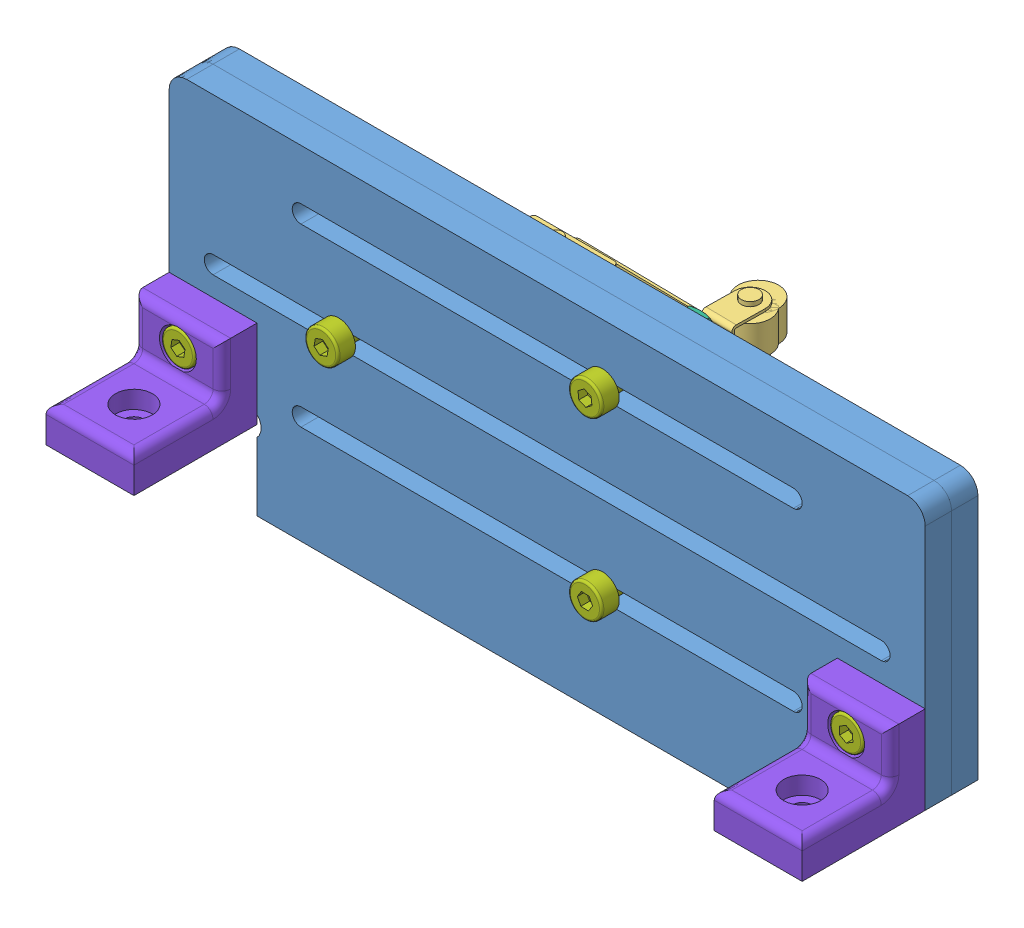
SolidWorks assembly fdc_ouvert, configuration Défaut. Lengths in mm.
Overall size (86 39 42.4).
21 component instances, 8 part files, 44 mates.
Components (placement in the parent):
- fdc-platine-1: fdc-platine [Défaut] at (140.8628 -70 0) x (0 0 1) z (0 -1 0) size (3 86 39)
- Grove microswitch v1.0-1: Grove microswitch v1.0 [Défaut] at (-48.6908 22.25 -3.344) x (-1 0 0) z (0 -1 0) size (41.8 22.4 23.6)
  - PCB grove 20x40-1: PCB grove 20x40 [Défaut] at (-1.988 -1.344 0) size (41.8 1.6 23.6)
  - microswitch 10T85-1: microswitch 10T85 [Défaut] at (9.562 0.256 0) size (22.48 22.4 6.4)
  - Connecteur Grove (coudé CMS)-1: Connecteur Grove (coudé CMS) [Défaut] at (-21.488 0.256 0) x (0 0 -1) z (0 1 0) size (12 10 5)
- entretoise-grove-1: entretoise-grove [Défaut] at (-66.7028 22.25 -2) x (1 0.000242 0) z (0 0 1) size (4 4 2)
- entretoise-grove-2: entretoise-grove [Défaut] at (-36.7028 32.25 -2) size (4 4 2)
- entretoise-grove-3: entretoise-grove [Défaut] at (-36.7028 12.25 -2) size (4 4 2)
- ecrou-h-2: ecrou-h [6007 HU M2] at (-36.7028 32.25 -5.2) x (-0.866025 0.5 0) z (-0.5 -0.866025 0) size (4 1.6 4.62)
- ecrou-h-3: ecrou-h [6007 HU M2] at (-36.7028 12.25 -5.2) x (0.866025 0.5 0) z (-0.5 0.866025 0) size (4 1.6 4.62)
- vis-chc-1: vis-chc [Vis CHC M2x12] at (-36.7028 32.25 6) x (0.144676 -0.989479 0) z (-0.989479 -0.144676 0) size (3.8 14 3.8)
- vis-chc-2: vis-chc [Vis CHC M2x12] at (-36.7028 12.25 6) x (0.999846 -0.017534 0) z (-0.017534 -0.999846 0) size (3.8 14 3.8)
- vis-chc-3: vis-chc [Vis CHC M2x12] at (-66.7028 22.25 6) x (-0.77641 0.630228 0) z (0.630228 0.77641 0) size (3.8 14 3.8)
- vis-chc-5: vis-chc [Vis CHC M2x10] at (-5 16 8) x (0.048861 -0.998806 0) z (-0.998806 -0.048861 0) size (3.8 12 3.8)
- vis-chc-6: vis-chc [Vis CHC M2x10] at (-81 16 8) x (-0.923728 -0.383049 0) z (-0.383049 0.923728 0) size (3.8 12 3.8)
- ecrou-h-6: ecrou-h [6007 HU M2] at (-81 16 -1.6) x (1 0 0) z (0 1 0) size (4 1.6 4.62)
- ecrou-h-8: ecrou-h [6007 HU M2] at (-5 16 -1.6) x (1 0 0) z (0 1 0) size (4 1.6 4.62)
- fdc-platine-2: fdc-platine [Défaut] at (140.8628 -70 3) x (0 0 1) z (0 -1 0) size (3 86 39)
- ecrou-h-4: ecrou-h [6007 HU M2] at (-66.7028 22.25 -5.2) x (1 0 0) z (0 1 0) size (4 1.6 4.62)
- equerre-basse-1: equerre-basse [Défaut] at (-81 9 6) size (10 10 14)
- equerre-basse-2: equerre-basse [Défaut] at (-5 9 6) size (10 10 14)
Mates (geometry in assembly coordinates):
- Coaxiale1: concentric anti-aligned: cylinder of Grove microswitch v1.0-1/PCB grove 20x40-1 through (-36.7028 12.25 -3.6) axis (0 0 1) radius 1.1; cylinder of entretoise-grove-3 through (-36.7028 12.25 0) axis (0 0 -1) radius 1.2
- Coïncidente4: coincident anti-aligned: plane of Grove microswitch v1.0-1/PCB grove 20x40-1 through (-46.7028 22.25 -2) normal (0 0 1); plane of entretoise-grove-3 through (-36.7028 12.25 -2) normal (0 0 -1)
- Coaxiale2: concentric anti-aligned: cylinder of Grove microswitch v1.0-1/PCB grove 20x40-1 through (-66.7028 22.25 -3.6) axis (0 0 1) radius 1.1; cylinder of entretoise-grove-1 through (-66.7028 22.25 0) axis (0 0 -1) radius 1.2
- Coïncidente5: coincident anti-aligned: plane of Grove microswitch v1.0-1/PCB grove 20x40-1 through (-46.7028 22.25 -2) normal (0 0 1); plane of entretoise-grove-1 through (-66.7028 22.25 -2) normal (0 0 -1)
- Coaxiale3: concentric anti-aligned: cylinder of Grove microswitch v1.0-1/PCB grove 20x40-1 through (-36.7028 32.25 -3.6) axis (0 0 1) radius 1.1; cylinder of entretoise-grove-2 through (-36.7028 32.25 0) axis (0 0 -1) radius 1.2
- Coïncidente6: coincident anti-aligned: plane of Grove microswitch v1.0-1/PCB grove 20x40-1 through (-46.7028 22.25 -2) normal (0 0 1); plane of entretoise-grove-2 through (-36.7028 32.25 -2) normal (0 0 -1)
- Coïncidente7: coincident anti-aligned: plane of cfc-platine-1 through (-8.8686 8.8686 0) normal (0 0 -1); plane of entretoise-grove-1 through (-66.7028 22.25 0) normal (0 0 1)
- Parallèle4: parallel aligned: plane of cfc-platine-1 through (-86 39 3) normal (-1 0 0); plane of Grove microswitch v1.0-1/PCB grove 20x40-1 through (-66.7028 22.25 -3.6) normal (-1 0 0)
- Parallèle3: parallel aligned: plane of cfc-platine-1 through (-10 0 3) normal (0 -1 0); plane of Grove microswitch v1.0-1/PCB grove 20x40-1 through (-46.7028 12.25 -3.6) normal (0 -1 0)
- Coaxiale4: concentric aligned: cylinder of Grove microswitch v1.0-1/PCB grove 20x40-1 through (-36.7028 32.25 -3.6) axis (0 0 1) radius 1.1; cylinder of vis-chc-1 through (-36.7028 32.25 -6) axis (0 0 1) radius 1
- Coaxiale5: concentric aligned: cylinder of Grove microswitch v1.0-1/PCB grove 20x40-1 through (-66.7028 22.25 -3.6) axis (0 0 1) radius 1.1; cylinder of vis-chc-3 through (-66.7028 22.25 -6) axis (0 0 1) radius 1
- Coaxiale6: concentric aligned: cylinder of Grove microswitch v1.0-1/PCB grove 20x40-1 through (-36.7028 12.25 -3.6) axis (0 0 1) radius 1.1; cylinder of vis-chc-2 through (-36.7028 12.25 -6) axis (0 0 1) radius 1
- Coaxiale7: concentric anti-aligned: cylinder of ecrou-h-2 through (-36.7028 32.25 -3.6) axis (0 0 -1) radius 0.7835; cylinder of vis-chc-1 through (-36.7028 32.25 -6) axis (0 0 1) radius 1
- Coaxiale8: concentric anti-aligned: cylinder of ecrou-h-3 through (-36.7028 12.25 -3.6) axis (0 0 -1) radius 0.7835; cylinder of vis-chc-2 through (-36.7028 12.25 -6) axis (0 0 1) radius 1
- Parallèle5: parallel aligned: plane of cfc-platine-1 through (0 39 3) normal (0 1 0); plane of ecrou-h-2 through (-37.8575 34.25 -3.6) normal (0 1 0)
- Parallèle7: parallel aligned: plane of ecrou-h-2 through (-37.8575 34.25 -3.6) normal (0 1 0); plane of ecrou-h-3 through (-37.8575 14.25 -3.6) normal (0 1 0)
- Tangent1: tangent anti-aligned: plane of cfc-platine-1 through (-15 31.25 3) normal (0 1 0); cylinder of vis-chc-1 through (-36.7028 32.25 -6) axis (0 0 1) radius 1
- Coïncidente17: coincident anti-aligned: plane of cfc-platine-1 through (-8.8686 8.8686 3) normal (0 0 1); plane of cfc-platine-2 through (-8.8686 8.8686 3) normal (0 0 -1)
- Coïncidente19: coincident aligned: plane of cfc-platine-1 through (-86 39 3) normal (-1 0 0); plane of cfc-platine-2 through (-86 39 6) normal (-1 0 0)
- Coïncidente20: coincident aligned: plane of cfc-platine-1 through (0 39 3) normal (0 1 0); plane of cfc-platine-2 through (0 39 6) normal (0 1 0)
- Coïncidente21: coincident anti-aligned: plane of vis-chc-3 through (-66.7028 22.25 6) normal (0 0 -1); plane of cfc-platine-2 through (-8.8686 8.8686 6) normal (0 0 1)
- Coaxiale9: concentric anti-aligned: cylinder of vis-chc-3 through (-66.7028 22.25 -6) axis (0 0 1) radius 1; cylinder of ecrou-h-4 through (-66.7028 22.25 -3.6) axis (0 0 -1) radius 0.7835
- Parallèle8: parallel aligned: plane of Grove microswitch v1.0-1/microswitch 10T85-1 through (-64.7028 19.25 -13.9) normal (-1 0 0); plane of ecrou-h-4 through (-68.7028 21.0953 -3.6) normal (-1 0 0)
- Coïncidente23: coincident anti-aligned: plane of Grove microswitch v1.0-1/PCB grove 20x40-1 through (-46.7028 22.25 -3.6) normal (0 0 -1); plane of ecrou-h-4 through (-64.7028 21.0953 -3.6) normal (0 0 1)
- Coïncidente24: coincident anti-aligned: plane of vis-chc-1 through (-36.7028 32.25 6) normal (0 0 -1); plane of cfc-platine-2 through (-8.8686 8.8686 6) normal (0 0 1)
- Coïncidente25: coincident anti-aligned: plane of Grove microswitch v1.0-1/PCB grove 20x40-1 through (-46.7028 22.25 -3.6) normal (0 0 -1); plane of ecrou-h-2 through (-37.8575 34.25 -3.6) normal (0 0 1)
- Parallèle9: parallel aligned: plane of Grove microswitch v1.0-1/PCB grove 20x40-1 through (-46.7028 32.25 -3.6) normal (0 1 0); plane of ecrou-h-2 through (-37.8575 34.25 -3.6) normal (0 1 0)
- Coïncidente28: coincident anti-aligned: plane of Grove microswitch v1.0-1/PCB grove 20x40-1 through (-46.7028 22.25 -3.6) normal (0 0 -1); plane of ecrou-h-3 through (-34.3934 12.25 -3.6) normal (0 0 1)
- Coïncidente29: coincident anti-aligned: plane of cfc-platine-2 through (-8.8686 8.8686 6) normal (0 0 1); plane of equerre-1 through (-81 9 6) normal (0 0 -1)
- Coïncidente30: coincident aligned: plane of cfc-platine-2 through (-86 39 6) normal (-1 0 0); plane of equerre-1 through (-86 19 10) normal (-1 0 0)
- Coïncidente31: coincident aligned: plane of cfc-platine-2 through (-78.726 9 6) normal (0 -1 0); plane of equerre-1 through (-86 9 10) normal (0 -1 0)
- Coaxiale10: concentric aligned: cylinder of equerre-1 through (-81 16 6) axis (0 0 1) radius 1.1; cylinder of vis-chc-6 through (-81 16 -2) axis (0 0 1) radius 1
- Coaxiale13: concentric anti-aligned: cylinder of cfc-platine-2 through (-5 16 6) axis (0 0 -1) radius 1; cylinder of vis-chc-5 through (-5 16 -2) axis (0 0 1) radius 1
- Coïncidente35: coincident anti-aligned: plane of equerre-1 through (-81 16 8) normal (0 0 1); plane of vis-chc-6 through (-81 16 8) normal (0 0 -1)
- Coïncidente36: coincident aligned: plane of equerre-1 through (-86 9 10) normal (0 -1 0); plane of equerre-2 through (-10 9 10) normal (0 -1 0)
- Coaxiale14: concentric anti-aligned: cylinder of cfc-platine-2 through (-5 16 6) axis (0 0 -1) radius 1; cylinder of equerre-2 through (-5 16 6) axis (0 0 1) radius 1.1
- Coaxiale17: concentric anti-aligned: cylinder of vis-chc-6 through (-81 16 -2) axis (0 0 1) radius 1; cylinder of ecrou-h-6 through (-81 16 0) axis (0 0 -1) radius 0.7835
- Coaxiale19: concentric anti-aligned: cylinder of vis-chc-5 through (-5 16 -2) axis (0 0 1) radius 1; cylinder of ecrou-h-8 through (-5 16 0) axis (0 0 -1) radius 0.7835
- Coïncidente38: coincident anti-aligned: plane of cfc-platine-1 through (-8.8686 8.8686 0) normal (0 0 -1); plane of ecrou-h-8 through (-3 14.8453 0) normal (0 0 1)
- Parallèle10: parallel aligned: plane of cfc-platine-1 through (0 9 3) normal (1 0 0); plane of ecrou-h-8 through (-3 17.1547 0) normal (1 0 0)
- Coïncidente44: coincident anti-aligned: plane of cfc-platine-1 through (-8.8686 8.8686 0) normal (0 0 -1); plane of ecrou-h-6 through (-79 14.8453 0) normal (0 0 1)
- Parallèle13: parallel aligned: plane of cfc-platine-1 through (-86 39 3) normal (-1 0 0); plane of ecrou-h-6 through (-83 14.8453 0) normal (-1 0 0)
- Coïncidente45: coincident anti-aligned: plane of cfc-platine-2 through (-8.8686 8.8686 6) normal (0 0 1); plane of equerre-2 through (-5 9 6) normal (0 0 -1)
- Coïncidente46: coincident anti-aligned: plane of vis-chc-5 through (-5 16 8) normal (0 0 -1); plane of equerre-2 through (-5 16 8) normal (0 0 1)
